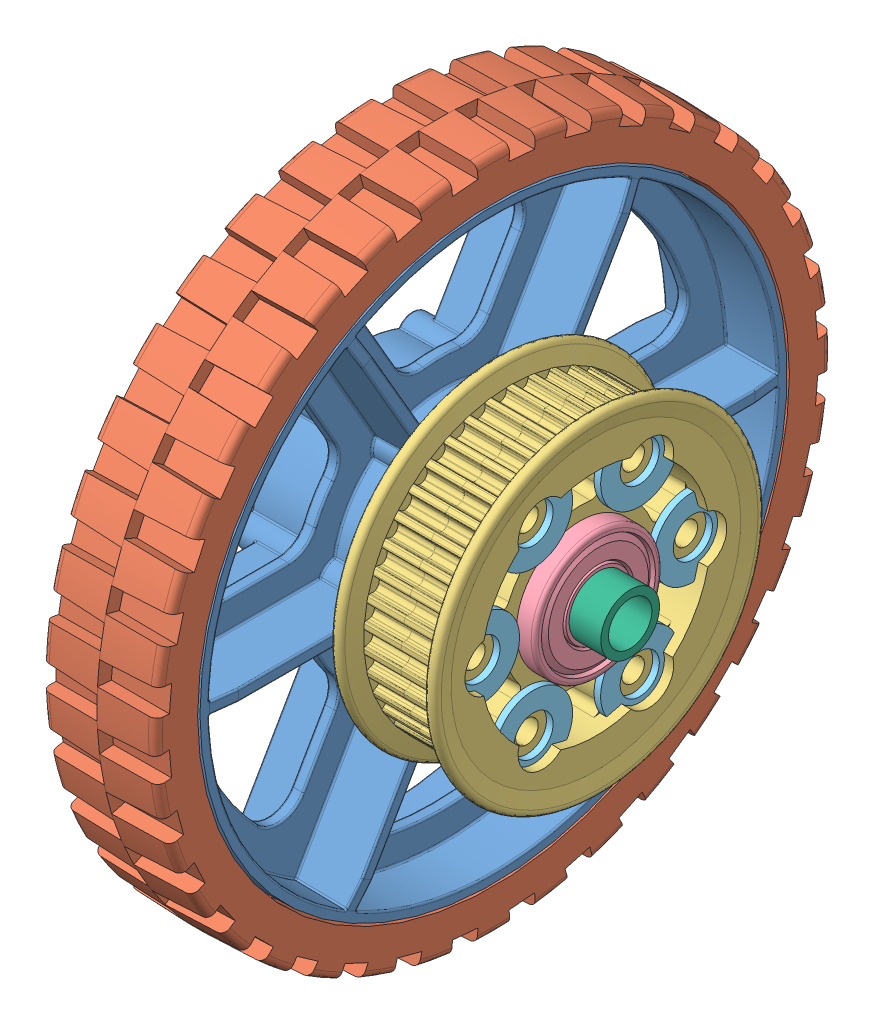
SolidWorks assembly 6 HiGrip with bearings, pulleys and spacers, configuration Default. Lengths in mm.
Overall size (85.56 152.4 152.4).
15 component instances, 7 part files, 0 mates.
Components (placement in the parent):
- 6 HiGrip Wheel Assembly Rev II-1: 6 HiGrip Wheel Assembly Rev II [Default] at (83.7987 67.439 110.9939) size (34.93 152.4 152.4)
  - 6 wheel Rev 4-1: 6 wheel Rev 4 [Default] at (-52.6446 9.4231 21.378) size (34.93 132.08 132.08)
  - 6 wheel tread II-1: 6 wheel tread II [Default] at (-65.3446 9.4231 21.378) x (0 0 -1) z (1 0 0) size (152.4 152.4 25.58)
- HalfPulley_42t5mm-1: HalfPulley_42t5mm [Default] at (47.6006 76.862 132.3719) x (1 0 0) z (0 -0.5 0.866025) size (13 74.23 74.23)
- HalfPulley_42t5mm-2: HalfPulley_42t5mm [Default] at (64.263 76.862 132.3719) x (-1 0 0) z (0 -0.499927 0.866067) size (13 74.23 74.23)
- Bearing_1614ZZ-1: Bearing_1614ZZ [Default] at (62.612 76.862 132.3719) x (0 0.904908 -0.425608) z (-1 0 0) size (28.58 28.58 9.53)
- Bearing_1614ZZ-2: Bearing_1614ZZ [Default] at (15.2791 76.862 132.3719) x (0 0.960548 -0.278115) z (1 0 0) size (28.58 28.58 9.53)
- Washer_5-16-1: Washer_5-16 [Default] at (63.247 76.8605 108.5602) x (0 -0.624545 -0.780988) z (1 0 0) size (17.53 17.53 1.47)
- Washer_5-16-2: Washer_5-16 [Default] at (63.247 97.4833 120.4656) x (0 -0.995817 0.091369) z (1 0 0) size (17.53 17.53 1.47)
- Washer_5-16-3: Washer_5-16 [Default] at (63.247 56.2398 144.2799) x (0 0.546149 0.837688) z (1 0 0) size (17.53 17.53 1.47)
- Washer_5-16-4: Washer_5-16 [Default] at (63.247 76.8625 156.1852) x (0 0.642695 -0.766122) z (1 0 0) size (17.53 17.53 1.47)
- Washer_5-16-5: Washer_5-16 [Default] at (63.247 97.4843 144.2781) x (0 0.936259 -0.351311) z (1 0 0) size (17.53 17.53 1.47)
- Washer_5-16-6: Washer_5-16 [Default] at (63.247 56.2388 120.4674) x (0 -0.160557 -0.987027) z (1 0 0) size (17.53 17.53 1.47)
- Spacer_0.28x0.382-1: Spacer_0.28x0.382 [Default] at (74.4865 76.862 132.3719) x (0 -0.996837 -0.07947) z (-1 0 0) size (13.16 13.16 7.11)
- Spacer_0.85x0.38-1: Spacer_0.85x0.38 [Default] at (-11.0734 76.862 132.3719) x (0 0.960548 -0.278115) z (1 0 0) size (19.05 19.05 21.59)
